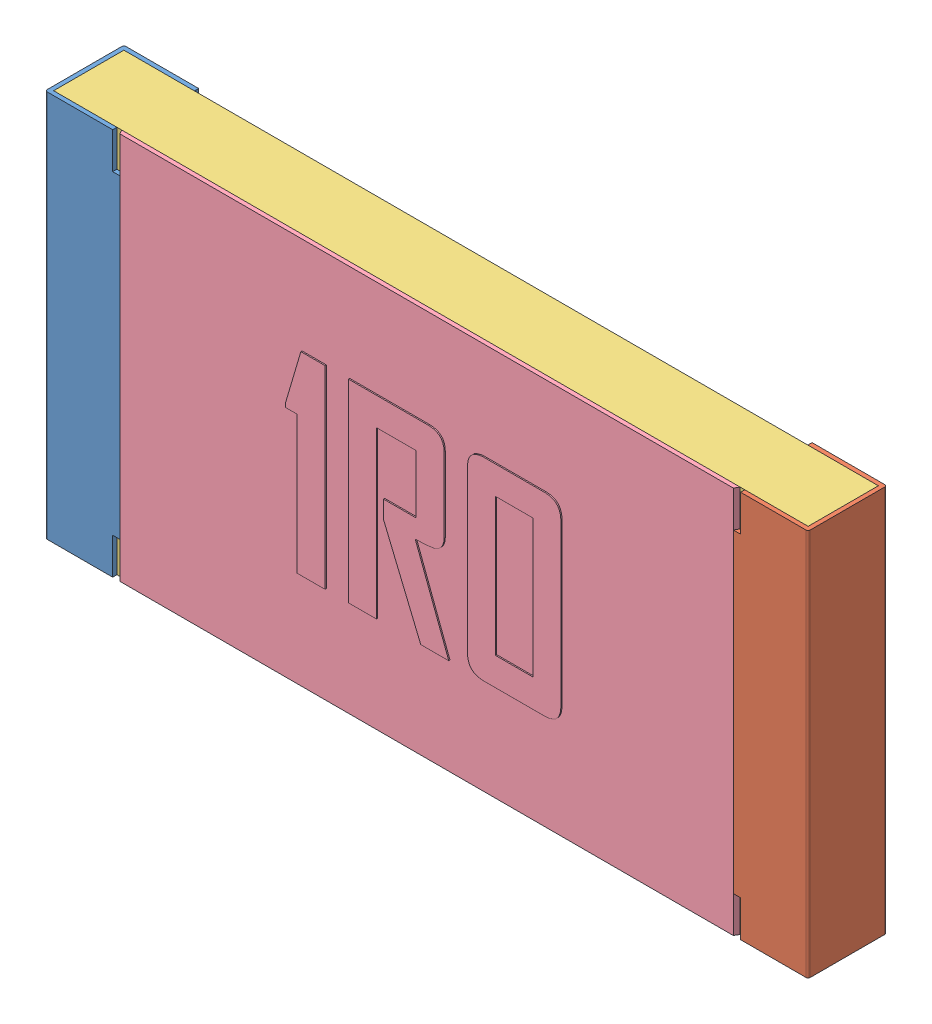
SolidWorks assembly Resistor_2512, configuration Default. Lengths in mm.
Overall size (6.3 3.2 0.66).
4 component instances, 4 part files, 0 mates.
Components (placement in the parent):
- Pin1Body-1: Pin1Body [Default] at (0 0 0.01) size (0.62 3.2 0.65)
- Pin2Body-1: Pin2Body [Default] at (0 0 0.01) size (0.62 3.2 0.65)
- CeramicBody-1: CeramicBody [Default] at (0 0 0.01) size (6.23 3.2 0.58)
- CoatingBody-1: CoatingBody [Default] at (0 0 0.01) size (5.11 3.2 0.05)
